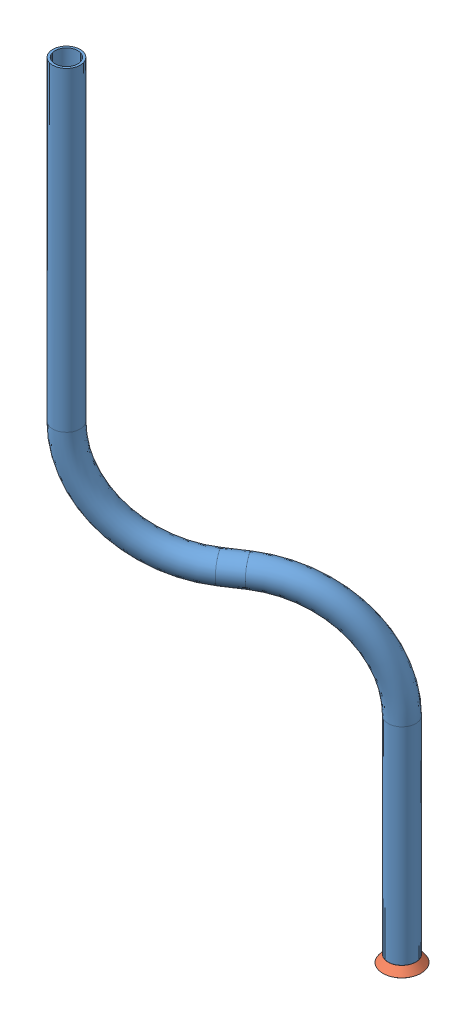
SolidWorks assembly Pipe 51, configuration Default. Lengths in mm.
Overall size (104.15 451.11 95.2).
2 component instances, 2 part files, 0 mates.
Components (placement in the parent):
- Pipe 46-1: Pipe 46 [Default<As Machined>] at origin size (101.62 447.16 92.69)
- Flared pipe end - .5 inch-1: Flared pipe end - .5 inch [Default<As Machined>] at (-347.2745 377.4661 370.4181) x (0.999949 0.007149 -0.00715) z (0.00715 -0.999974 0) size (17.59 17.59 3.89)
